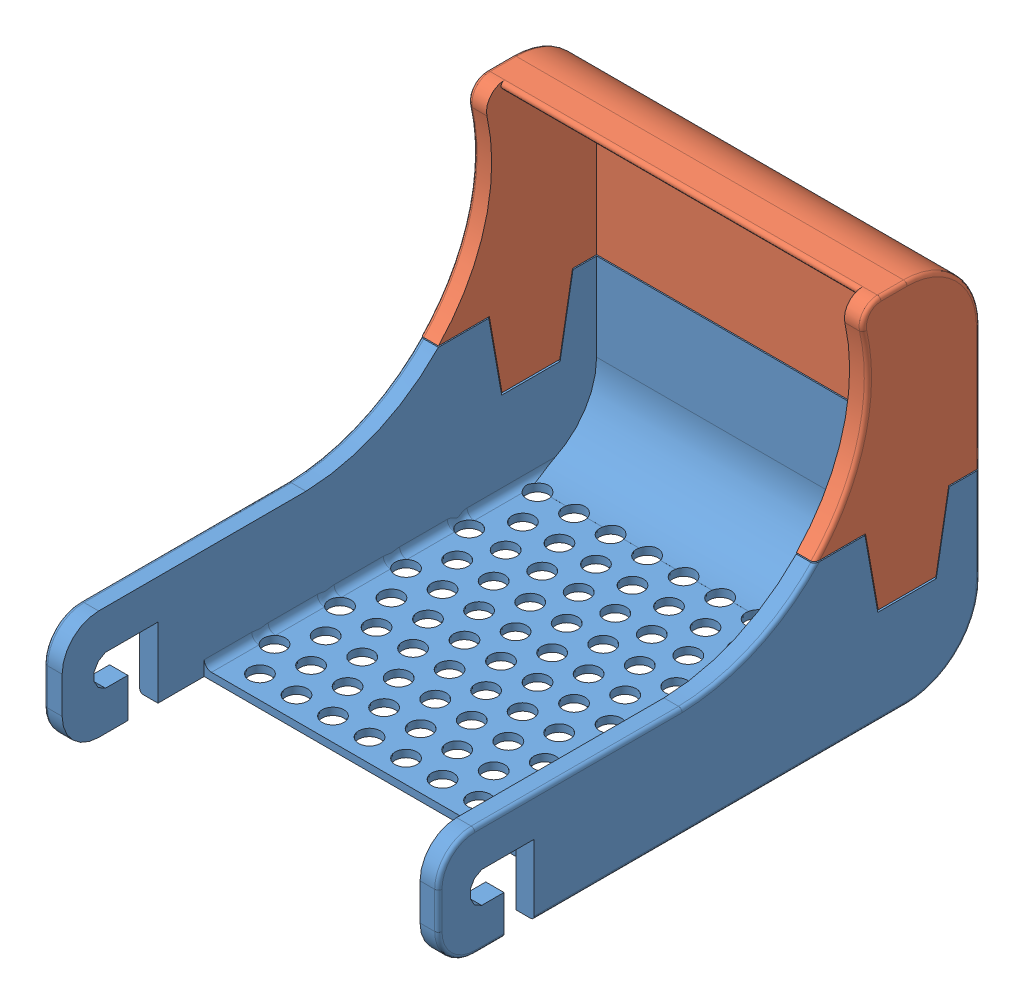
SolidWorks assembly Quick fix assmble, configuration Default. Lengths in mm.
Overall size (109.09 100.33 176).
2 component instances, 2 part files, 1 mates.
Components (placement in the parent):
- Tray top v2-1: Tray top v2 [Default] at (-8.1707 90.7352 140.9874) size (108.17 46 148.35)
- Tray bottom v2-1: Tray bottom v2 [Default] at (-8.1707 91.0602 140.9767) size (108.17 73.8 45.41)
Mates (geometry in assembly coordinates):
- Coincident1: coincident: plane of Tray top v2-1 through (100.8293 195.7352 232.3441) normal (1 0 0); plane of Tray bottom v2-1 through (100.8293 196.0602 232.3334) normal (1 0 0)
